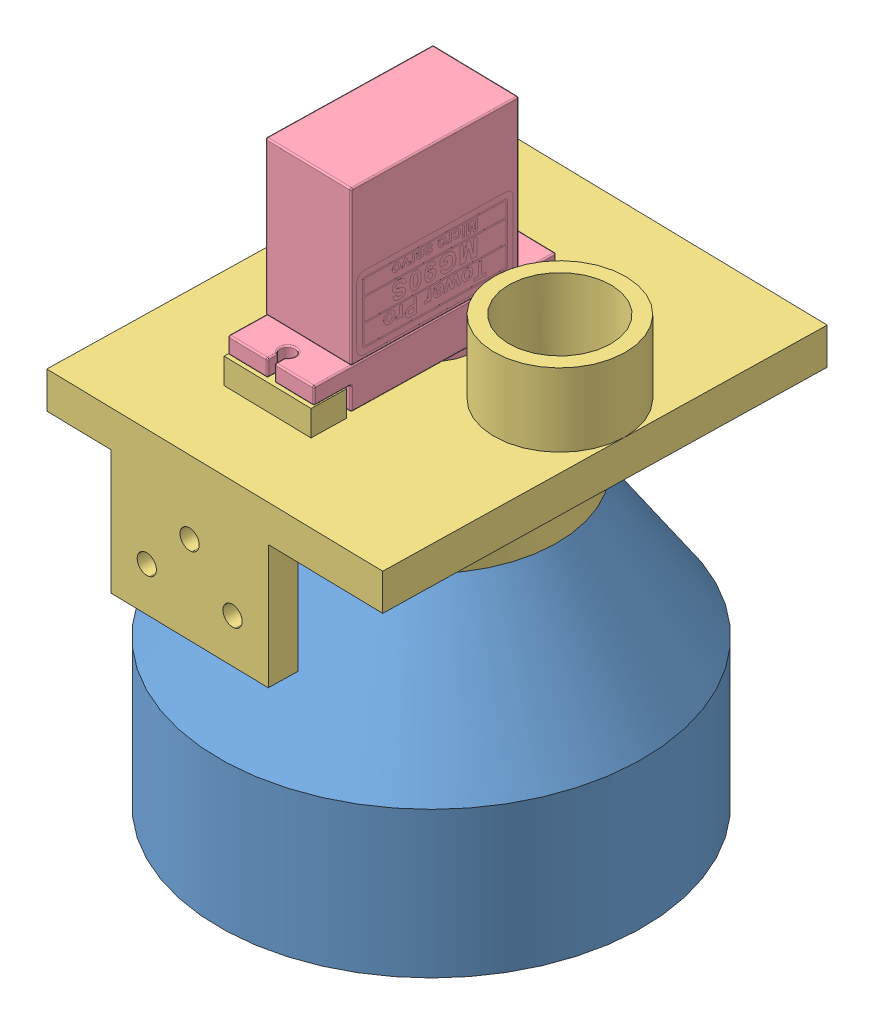
SolidWorks assembly Montaj1, configuration Varsayılan. Lengths in mm.
Overall size (59.69 84.21 62.83).
6 component instances, 6 part files, 16 mates.
Components (placement in the parent):
- huni-1: huni [Varsayılan] at (-10.3323 4.5432 57.7153) x (0.029512 0 -0.999564) z (0.999564 0 0.029512) size (58 42 58)
- SG90 - Micro Servo 9g - Tower Pro.1-1: SG90 - Micro Servo 9g - Tower Pro.1 [Peça] at (-10.4257 53.1518 63.1489) x (-0.020907 0 0.999781) z (0.999781 0 0.020907) (suppressed, hidden)
- hazne-1: hazne [Varsayılan] at (-10.3323 27.5432 57.7153) x (-0.026649 0 -0.999645) z (0.999645 0 -0.026649) size (25 8 24.16)
- SG90 - Micro Servo 9g - Tower Pro.4-1: SG90 - Micro Servo 9g - Tower Pro.4 [Peça] at (-10.318 32.0518 58) x (-0.998715 0 -0.050679) z (-0.050679 0 0.998715) (suppressed, hidden)
- kasa-1: kasa [Varsayılan] at (-10.318 36.9518 58) x (-0.020907 0 0.999781) z (-0.999781 0 -0.020907) size (59.65 32 47)
- MG90s_servo-1: MG90s_servo [Default] at (-10.442 47.7518 62.9641) x (0.020907 0 -0.999781) z (0 1 0) size (32.5 12 34)
Mates (geometry in assembly coordinates):
- Eş Merkezli1: concentric anti-aligned: circle of SG90 - Micro Servo 9g - Tower Pro.1-1; circle of huni-1
- Eş Merkezli2: concentric aligned: circle of huni-1; circle of hazne-1
- Uzaklık1: distance = 1 mm anti-aligned: plane of hazne-1 through (-2.3351 27.5432 57.5021) normal (0 -1 0); plane of huni-1 through (-10.3323 26.5432 57.7153) normal (0 1 0)
- Çakışık2: coincident anti-aligned: plane of hazne-1 through (-2.3351 32.5432 57.5021) normal (0 1 0); plane of SG90 - Micro Servo 9g - Tower Pro.4-1 through (-10.318 32.0518 58) normal (0 -1 0)
- Eş Merkezli3: concentric aligned: cylinder of SG90 - Micro Servo 9g - Tower Pro.4-1 through (-10.318 33.4518 58) axis (0 -1 0) radius 3.45; cylinder of hazne-1 through (-10.3323 32.5432 57.7153) axis (0 -1 0) radius 12.5
- Eş Merkezli4: concentric anti-aligned: cylinder of hazne-1 through (-10.1517 30.0432 64.1627) axis (0 1 0) radius 0.6; cylinder of SG90 - Micro Servo 9g - Tower Pro.4-1 through (-10.6449 32.0518 64.4417) axis (0 -1 0) radius 0.6
- Çakışık3: coincident anti-aligned: plane of SG90 - Micro Servo 9g - Tower Pro.1-1 through (-10.318 33.8518 58) normal (0 -1 0); plane of SG90 - Micro Servo 9g - Tower Pro.4-1 through (-10.318 33.8518 58) normal (0 1 0)
- Çakışık4: coincident aligned: plane of SG90 - Micro Servo 9g - Tower Pro.1-1 through (-10.318 36.9518 58) normal (0 -1 0); plane of kasa-1 through (-10.318 36.9518 58) normal (0 -1 0)
- Paralel1: parallel aligned: plane of SG90 - Micro Servo 9g - Tower Pro.1-1 through (-16.2066 45.5018 47.8247) normal (-0.999781 0 -0.020907); plane of kasa-1 through (-29.7385 41.9518 30.0807) normal (-0.999781 0 -0.020907)
- Eş Merkezli5: concentric aligned: cylinder of SG90 - Micro Servo 9g - Tower Pro.1-1 through (-10.318 36.9518 58) axis (0 1 0) radius 6.1; cylinder of kasa-1 through (-10.318 36.9518 58) axis (0 1 0) radius 6.6401
- Concentric1: concentric anti-aligned: cylinder of hazne-1 through (-10.3323 32.5432 57.7153) axis (0 -1 0) radius 12.5; cylinder of MG90s_servo-1 through (-10.3323 38.2518 57.7153) axis (0 1 0) radius 6
- Parallel1: parallel aligned: plane of kasa-1 through (-16.1798 45.4518 46.1279) normal (-0.999781 0 -0.020907); plane of MG90s_servo-1 through (-16.4407 45.4518 62.8387) normal (-0.999781 0 -0.020907)
- Coincident3: coincident anti-aligned: plane of kasa-1 through (-10.318 45.4518 58) normal (0 1 0); plane of MG90s_servo-1 through (-10.442 45.4518 62.9641) normal (0 -1 0)
- Width1: width anti-aligned: plane of MG90s_servo-1 through (-10.7818 45.4518 79.2106) normal (-0.020907 0 0.999781); plane of MG90s_servo-1 through (-10.1023 45.4518 46.7177) normal (0.020907 0 -0.999781); plane of kasa-1 through (-4.0142 45.4518 46.3823) normal (0.020907 0 -0.999781); plane of kasa-1 through (-4.713 45.4518 79.8002) normal (-0.020907 0 0.999781)
- Width2: width anti-aligned: plane of MG90s_servo-1 through (-4.6785 68.7518 74.3371) normal (0.999781 0 0.020907); plane of MG90s_servo-1 through (-16.6759 68.7518 74.0862) normal (-0.999781 0 -0.020907); plane of kasa-1 through (-16.8699 45.4518 79.546) normal (-0.999781 0 -0.020907); plane of kasa-1 through (-4.713 45.4518 79.8002) normal (0.999781 0 0.020907)
- Coincident4: coincident anti-aligned: plane of huni-1 through (-10.3323 26.5432 57.7153) normal (0 1 0); plane of kasa-1 through (-10.3323 26.5432 57.7153) normal (0 -1 0)
